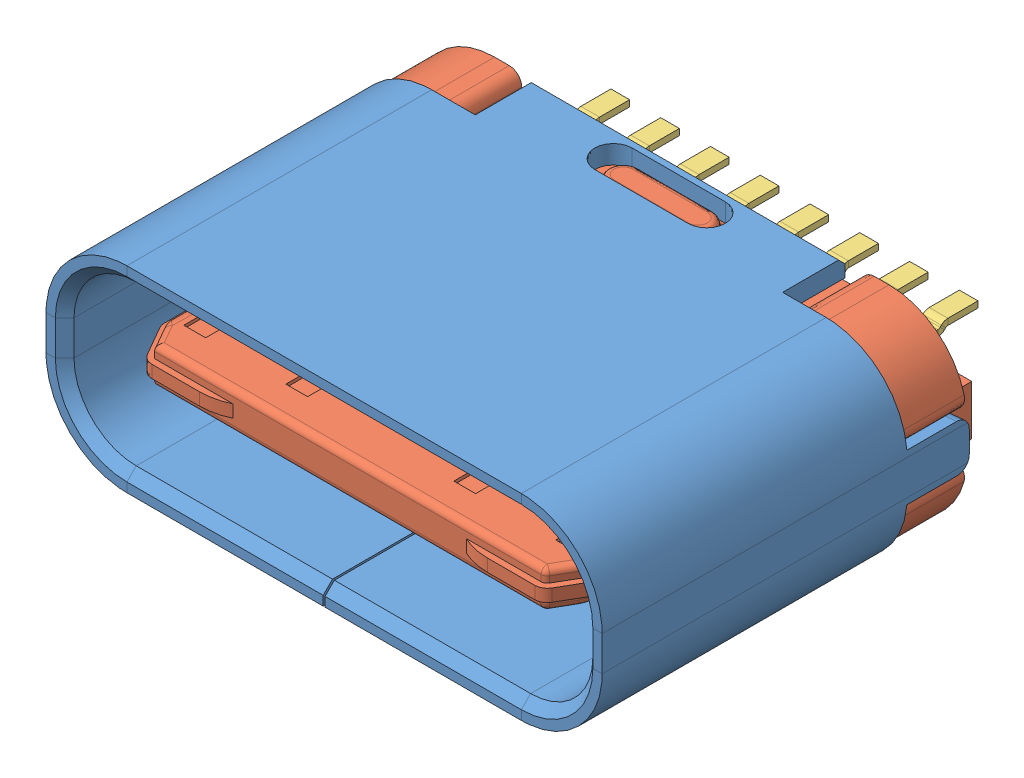
SolidWorks assembly USB Type C Socket^PCB_Riden TC64 Module 01a(2)_Riden TC64 Module 01a, configuration 默认. Lengths in mm.
Overall size (8.95 3.16 7.36).
18 component instances, 3 part files, 0 mates.
Components (placement in the parent):
- USB_C_SHELL^USB Type C Socket_PCB_Riden TC64 Module 01a(2)_Riden TC64 Module 01a-1: USB_C_SHELL^USB Type C Socket_PCB_Riden TC64 Module 01a(2)_Riden TC64 Module 01a [默认] at origin size (8.95 3.16 5.9) (virtual)
- USB_C_Body^USB Type C Socket_PCB_Riden TC64 Module 01a(2)_Riden TC64 Module 01a-1: USB_C_Body^USB Type C Socket_PCB_Riden TC64 Module 01a(2)_Riden TC64 Module 01a [默认] at (0 0 -1.21) size (8.77 3.06 6.05) (virtual)
- USB_C_PIN^USB Type C Socket_PCB_Riden TC64 Module 01a(2)_Riden TC64 Module 01a-1: USB_C_PIN^USB Type C Socket_PCB_Riden TC64 Module 01a(2)_Riden TC64 Module 01a [默认] at (3 0.5 -3.47) x (-1 0 0) z (0 -1 0) size (0.3 1.94 0.21) (virtual)
- USB_C_PIN^USB Type C Socket_PCB_Riden TC64 Module 01a(2)_Riden TC64 Module 01a-2: USB_C_PIN^USB Type C Socket_PCB_Riden TC64 Module 01a(2)_Riden TC64 Module 01a [默认] at (2.2 0.5 -3.47) x (-1 0 0) z (0 -1 0) size (0.3 1.94 0.21) (virtual)
- USB_C_PIN^USB Type C Socket_PCB_Riden TC64 Module 01a(2)_Riden TC64 Module 01a-3: USB_C_PIN^USB Type C Socket_PCB_Riden TC64 Module 01a(2)_Riden TC64 Module 01a [默认] at (1.4 0.5 -3.47) x (-1 0 0) z (0 -1 0) size (0.3 1.94 0.21) (virtual)
- USB_C_PIN^USB Type C Socket_PCB_Riden TC64 Module 01a(2)_Riden TC64 Module 01a-4: USB_C_PIN^USB Type C Socket_PCB_Riden TC64 Module 01a(2)_Riden TC64 Module 01a [默认] at (0.6 0.5 -3.47) x (-1 0 0) z (0 -1 0) size (0.3 1.94 0.21) (virtual)
- USB_C_PIN^USB Type C Socket_PCB_Riden TC64 Module 01a(2)_Riden TC64 Module 01a-5: USB_C_PIN^USB Type C Socket_PCB_Riden TC64 Module 01a(2)_Riden TC64 Module 01a [默认] at (-0.2 0.5 -3.47) x (-1 0 0) z (0 -1 0) size (0.3 1.94 0.21) (virtual)
- USB_C_PIN^USB Type C Socket_PCB_Riden TC64 Module 01a(2)_Riden TC64 Module 01a-6: USB_C_PIN^USB Type C Socket_PCB_Riden TC64 Module 01a(2)_Riden TC64 Module 01a [默认] at (-2.6 0.5 -3.47) x (-1 0 0) z (0 -1 0) size (0.3 1.94 0.21) (virtual)
- USB_C_PIN^USB Type C Socket_PCB_Riden TC64 Module 01a(2)_Riden TC64 Module 01a-7: USB_C_PIN^USB Type C Socket_PCB_Riden TC64 Module 01a(2)_Riden TC64 Module 01a [默认] at (-1.8 0.5 -3.47) x (-1 0 0) z (0 -1 0) size (0.3 1.94 0.21) (virtual)
- USB_C_PIN^USB Type C Socket_PCB_Riden TC64 Module 01a(2)_Riden TC64 Module 01a-8: USB_C_PIN^USB Type C Socket_PCB_Riden TC64 Module 01a(2)_Riden TC64 Module 01a [默认] at (-3 -0.45 -3.45) x (1 0 0) z (0 1 0) size (0.3 1.94 0.21) (virtual)
- USB_C_PIN^USB Type C Socket_PCB_Riden TC64 Module 01a(2)_Riden TC64 Module 01a-9: USB_C_PIN^USB Type C Socket_PCB_Riden TC64 Module 01a(2)_Riden TC64 Module 01a [默认] at (-2.2 -0.45 -3.45) x (1 0 0) z (0 1 0) size (0.3 1.94 0.21) (virtual)
- USB_C_PIN^USB Type C Socket_PCB_Riden TC64 Module 01a(2)_Riden TC64 Module 01a-10: USB_C_PIN^USB Type C Socket_PCB_Riden TC64 Module 01a(2)_Riden TC64 Module 01a [默认] at (-1.4 -0.45 -3.45) x (1 0 0) z (0 1 0) size (0.3 1.94 0.21) (virtual)
- USB_C_PIN^USB Type C Socket_PCB_Riden TC64 Module 01a(2)_Riden TC64 Module 01a-11: USB_C_PIN^USB Type C Socket_PCB_Riden TC64 Module 01a(2)_Riden TC64 Module 01a [默认] at (-0.6 -0.45 -3.45) x (1 0 0) z (0 1 0) size (0.3 1.94 0.21) (virtual)
- USB_C_PIN^USB Type C Socket_PCB_Riden TC64 Module 01a(2)_Riden TC64 Module 01a-12: USB_C_PIN^USB Type C Socket_PCB_Riden TC64 Module 01a(2)_Riden TC64 Module 01a [默认] at (1 -0.45 -3.45) x (1 0 0) z (0 1 0) size (0.3 1.94 0.21) (virtual)
- USB_C_PIN^USB Type C Socket_PCB_Riden TC64 Module 01a(2)_Riden TC64 Module 01a-13: USB_C_PIN^USB Type C Socket_PCB_Riden TC64 Module 01a(2)_Riden TC64 Module 01a [默认] at (0.2 -0.45 -3.45) x (1 0 0) z (0 1 0) size (0.3 1.94 0.21) (virtual)
- USB_C_PIN^USB Type C Socket_PCB_Riden TC64 Module 01a(2)_Riden TC64 Module 01a-14: USB_C_PIN^USB Type C Socket_PCB_Riden TC64 Module 01a(2)_Riden TC64 Module 01a [默认] at (1.8 -0.45 -3.45) x (1 0 0) z (0 1 0) size (0.3 1.94 0.21) (virtual)
- USB_C_PIN^USB Type C Socket_PCB_Riden TC64 Module 01a(2)_Riden TC64 Module 01a-15: USB_C_PIN^USB Type C Socket_PCB_Riden TC64 Module 01a(2)_Riden TC64 Module 01a [默认] at (2.6 -0.45 -3.45) x (1 0 0) z (0 1 0) size (0.3 1.94 0.21) (virtual)
- USB_C_PIN^USB Type C Socket_PCB_Riden TC64 Module 01a(2)_Riden TC64 Module 01a-16: USB_C_PIN^USB Type C Socket_PCB_Riden TC64 Module 01a(2)_Riden TC64 Module 01a [默认] at (-1 0.5 -3.47) x (-1 0 0) z (0 -1 0) size (0.3 1.94 0.21) (virtual)
